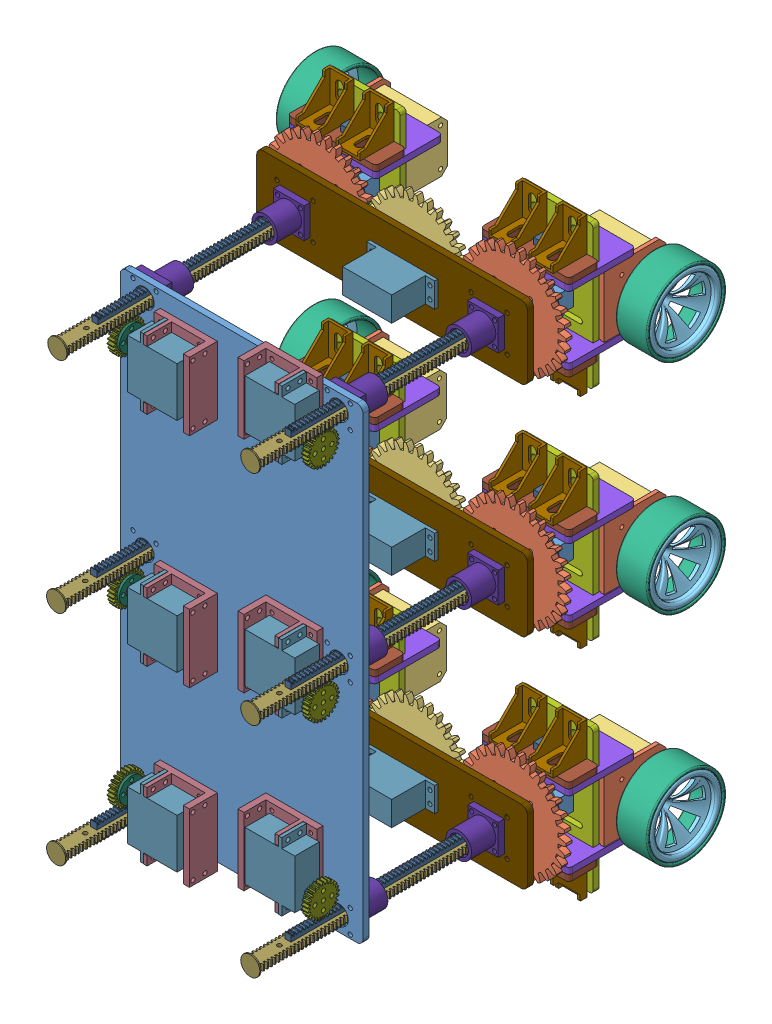
SolidWorks assembly 装配体1A, configuration 默认. Lengths in mm.
Overall size (307.3 487 335.01).
181 component instances, 21 part files, 77 mates.
Components (placement in the parent):
- 6-1: 6 [默认] at (6.6462 9.8364 382.5) size (200 385 5)
- 装配体1-1: 装配体1 [默认] at (-137.0038 190.3841 181.1965) x (0 -1 0) z (1 0 0) size (127 334.01 110.15)
  - 电机支架-1: 电机支架 [默认] at (0.5477 -19.153 31) size (51 51 56)
  - 电机驱动器-1: 电机驱动器 [默认] at (0.5477 7.847 31) size (42.3 42.3 61)
  - 六角联轴器-1: 六角联轴器 [默认] at (0.5477 7.847 16) x (1 0 0) z (0 1 0) size (14 18 12.12)
  - 整个车轮-1: 整个车轮 [默认] at (-1.2111 6.0898 64.1725) x (-0.823184 -0.567775 0) z (0 0 -1) size (84.94 84.94 26)
    - 轮胎-1: 轮胎 [默认] at (-2.4455 0.4479 54.1725) size (63.39 63.18 21.57)
    - 轮胎外-1: 轮胎外 [默认] at (-2.4455 0.4479 48.1725) x (0.923728 0.383049 0) z (0.383049 -0.923728 0) size (65 26 65)
  - 1-1: 1 [默认] at (0.5477 -27.153 60.15) x (1 0 0) z (0 1 0) size (118 63 5)
  - 2-1: 2 [默认] at (31.0477 -24.653 63.65) x (0 0 -1) z (-1 0 0) size (73 55 5)
  - 2-2: 2 [默认] at (-24.9523 -24.653 63.65) x (0 0 -1) z (-1 0 0) size (73 55 5)
  - 2020角件-1: 2020角件 [Default] at (36.0477 -27.153 37.15) x (0 -1 0) z (0 0 1) size (28 28 20)
  - 2020角件-2: 2020角件 [Default] at (-34.9523 -27.153 90.15) x (0 -1 0) z (0 0 -1) size (28 28 20)
  - 3-1: 3 [默认] at (-1.9523 -27.153 66.15) x (1 0 0) z (0 0 -1) size (38 220 5)
  - 3-2: 3 [默认] at (3.0477 -27.153 61.15) x (-1 0 0) z (0 0 1) size (38 220 5)
  - 4-1: 4 [默认] at (-29.9523 -39.653 63.65) x (0 0 -1) z (-1 0 0) size (73 25 5)
  - 2020角件-3: 2020角件 [Default] at (-34.9523 -27.153 57.15) x (0 -1 0) z (0 0 -1) size (28 28 20)
  - 4-2: 4 [默认] at (36.0477 -39.653 63.65) x (0 0 -1) z (-1 0 0) size (73 25 5)
  - 2020角件-4: 2020角件 [Default] at (36.0477 -27.153 70.15) x (0 -1 0) z (0 0 1) size (28 28 20)
  - 5-1: 5 [默认] at (-1.9523 -260.723 -17.3052) x (0 0 -1) z (1 0 0) size (15.81 251 15.81)
- 装配体3-1: 装配体3 [默认] at (-35.9644 156.0912 456.1) x (-1 0 0) z (0 0 -1) size (62.5 56.25 28.25)
  - 20KG大舵机支架-1: 20KG大舵机支架 [Default] at (3.3894 4.911 63.6) size (47 56 25.2)
  - 20KG大舵机-1: 20KG大舵机 [Default] at (26.3894 5.161 53.5) x (0 -1 0) z (-1 0 0) size (56 20.2 45)
  - 舵盘 (1)-1: 舵盘 (1) [默认] at (34.8894 14.911 53.5) x (0 0 1) z (-1 0 0) size (20 20 4.5)
  - 齿轮3-1: 齿轮3 [默认] at (39.8894 -17.7771 74.1398) x (0 0 1) z (-1 0 0) size (26.3 26.25 5)
- 装配体1-2: 装配体1 [默认] at (-137.0038 10.3841 182.1965) x (0 -1 0) z (1 0 0) size (127 334.01 110.15)
  - 电机支架-1: 电机支架 [默认] at (0.5477 -19.153 31) size (51 51 56)
  - 电机驱动器-1: 电机驱动器 [默认] at (0.5477 7.847 31) size (42.3 42.3 61)
  - 六角联轴器-1: 六角联轴器 [默认] at (0.5477 7.847 16) x (1 0 0) z (0 1 0) size (14 18 12.12)
  - 整个车轮-1: 整个车轮 [默认] at (-1.2111 6.0898 64.1725) x (-0.823184 -0.567775 0) z (0 0 -1) size (84.94 84.94 26)
    - 轮胎-1: 轮胎 [默认] at (-2.4455 0.4479 54.1725) size (63.39 63.18 21.57)
    - 轮胎外-1: 轮胎外 [默认] at (-2.4455 0.4479 48.1725) x (0.923728 0.383049 0) z (0.383049 -0.923728 0) size (65 26 65)
  - 1-1: 1 [默认] at (0.5477 -27.153 60.15) x (1 0 0) z (0 1 0) size (118 63 5)
  - 2-1: 2 [默认] at (31.0477 -24.653 63.65) x (0 0 -1) z (-1 0 0) size (73 55 5)
  - 2-2: 2 [默认] at (-24.9523 -24.653 63.65) x (0 0 -1) z (-1 0 0) size (73 55 5)
  - 2020角件-1: 2020角件 [Default] at (36.0477 -27.153 37.15) x (0 -1 0) z (0 0 1) size (28 28 20)
  - 2020角件-2: 2020角件 [Default] at (-34.9523 -27.153 90.15) x (0 -1 0) z (0 0 -1) size (28 28 20)
  - 3-1: 3 [默认] at (-1.9523 -27.153 66.15) x (1 0 0) z (0 0 -1) size (38 220 5)
  - 3-2: 3 [默认] at (3.0477 -27.153 61.15) x (-1 0 0) z (0 0 1) size (38 220 5)
  - 4-1: 4 [默认] at (-29.9523 -39.653 63.65) x (0 0 -1) z (-1 0 0) size (73 25 5)
  - 2020角件-3: 2020角件 [Default] at (-34.9523 -27.153 57.15) x (0 -1 0) z (0 0 -1) size (28 28 20)
  - 4-2: 4 [默认] at (36.0477 -39.653 63.65) x (0 0 -1) z (-1 0 0) size (73 25 5)
  - 2020角件-4: 2020角件 [Default] at (36.0477 -27.153 70.15) x (0 -1 0) z (0 0 1) size (28 28 20)
  - 5-1: 5 [默认] at (-1.9523 -260.723 -17.3052) x (0 0 -1) z (1 0 0) size (15.81 251 15.81)
- 装配体3-2: 装配体3 [默认] at (-35.9644 -23.777 456.1) x (-1 0 0) z (0 0 -1) size (62.5 56.25 28.25)
  - 20KG大舵机支架-1: 20KG大舵机支架 [Default] at (3.3894 4.911 63.6) size (47 56 25.2)
  - 20KG大舵机-1: 20KG大舵机 [Default] at (26.3894 5.161 53.5) x (0 -1 0) z (-1 0 0) size (56 20.2 45)
  - 舵盘 (1)-1: 舵盘 (1) [默认] at (34.8894 14.911 53.5) x (0 0 1) z (-1 0 0) size (20 20 4.5)
  - 齿轮3-1: 齿轮3 [默认] at (39.8894 -17.7771 74.1398) x (0 0 1) z (-1 0 0) size (26.3 26.25 5)
- 装配体1-3: 装配体1 [默认] at (-137.0038 -169.6159 182.1965) x (0 -1 0) z (1 0 0) size (127 334.01 110.15)
  - 电机支架-1: 电机支架 [默认] at (0.5477 -19.153 31) size (51 51 56)
  - 电机驱动器-1: 电机驱动器 [默认] at (0.5477 7.847 31) size (42.3 42.3 61)
  - 六角联轴器-1: 六角联轴器 [默认] at (0.5477 7.847 16) x (1 0 0) z (0 1 0) size (14 18 12.12)
  - 整个车轮-1: 整个车轮 [默认] at (-1.2111 6.0898 64.1725) x (-0.823184 -0.567775 0) z (0 0 -1) size (84.94 84.94 26)
    - 轮胎-1: 轮胎 [默认] at (-2.4455 0.4479 54.1725) size (63.39 63.18 21.57)
    - 轮胎外-1: 轮胎外 [默认] at (-2.4455 0.4479 48.1725) x (0.923728 0.383049 0) z (0.383049 -0.923728 0) size (65 26 65)
  - 1-1: 1 [默认] at (0.5477 -27.153 60.15) x (1 0 0) z (0 1 0) size (118 63 5)
  - 2-1: 2 [默认] at (31.0477 -24.653 63.65) x (0 0 -1) z (-1 0 0) size (73 55 5)
  - 2-2: 2 [默认] at (-24.9523 -24.653 63.65) x (0 0 -1) z (-1 0 0) size (73 55 5)
  - 2020角件-1: 2020角件 [Default] at (36.0477 -27.153 37.15) x (0 -1 0) z (0 0 1) size (28 28 20)
  - 2020角件-2: 2020角件 [Default] at (-34.9523 -27.153 90.15) x (0 -1 0) z (0 0 -1) size (28 28 20)
  - 3-1: 3 [默认] at (-1.9523 -27.153 66.15) x (1 0 0) z (0 0 -1) size (38 220 5)
  - 3-2: 3 [默认] at (3.0477 -27.153 61.15) x (-1 0 0) z (0 0 1) size (38 220 5)
  - 4-1: 4 [默认] at (-29.9523 -39.653 63.65) x (0 0 -1) z (-1 0 0) size (73 25 5)
  - 2020角件-3: 2020角件 [Default] at (-34.9523 -27.153 57.15) x (0 -1 0) z (0 0 -1) size (28 28 20)
  - 4-2: 4 [默认] at (36.0477 -39.653 63.65) x (0 0 -1) z (-1 0 0) size (73 25 5)
  - 2020角件-4: 2020角件 [Default] at (36.0477 -27.153 70.15) x (0 -1 0) z (0 0 1) size (28 28 20)
  - 5-1: 5 [默认] at (-1.9523 -260.723 -17.3052) x (0 0 -1) z (1 0 0) size (15.81 251 15.81)
- 装配体3-3: 装配体3 [默认] at (-35.9644 -166.195 456.1) x (-1 0 0) z (0 0 -1) size (62.5 56.25 28.25)
  - 20KG大舵机支架-1: 20KG大舵机支架 [Default] at (3.3894 4.911 63.6) size (47 56 25.2)
  - 20KG大舵机-1: 20KG大舵机 [Default] at (26.3894 5.161 53.5) x (0 -1 0) z (-1 0 0) size (56 20.2 45)
  - 舵盘 (1)-1: 舵盘 (1) [默认] at (34.8894 14.911 53.5) x (0 0 1) z (-1 0 0) size (20 20 4.5)
  - 齿轮3-1: 齿轮3 [默认] at (39.8894 -17.7771 74.1398) x (0 0 1) z (-1 0 0) size (26.3 26.25 5)
- 装配体1-4: 装配体1 [默认] at (150.2962 -170.7113 182.1965) x (0 1 0) z (-1 0 0) size (127 334.01 110.15)
  - 电机支架-1: 电机支架 [默认] at (0.5477 -19.153 31) size (51 51 56)
  - 电机驱动器-1: 电机驱动器 [默认] at (0.5477 7.847 31) size (42.3 42.3 61)
  - 六角联轴器-1: 六角联轴器 [默认] at (0.5477 7.847 16) x (1 0 0) z (0 1 0) size (14 18 12.12)
  - 整个车轮-1: 整个车轮 [默认] at (-1.2111 6.0898 64.1725) x (-0.823184 -0.567775 0) z (0 0 -1) size (84.94 84.94 26)
    - 轮胎-1: 轮胎 [默认] at (-2.4455 0.4479 54.1725) size (63.39 63.18 21.57)
    - 轮胎外-1: 轮胎外 [默认] at (-2.4455 0.4479 48.1725) x (0.923728 0.383049 0) z (0.383049 -0.923728 0) size (65 26 65)
  - 1-1: 1 [默认] at (0.5477 -27.153 60.15) x (1 0 0) z (0 1 0) size (118 63 5)
  - 2-1: 2 [默认] at (31.0477 -24.653 63.65) x (0 0 -1) z (-1 0 0) size (73 55 5)
  - 2-2: 2 [默认] at (-24.9523 -24.653 63.65) x (0 0 -1) z (-1 0 0) size (73 55 5)
  - 2020角件-1: 2020角件 [Default] at (36.0477 -27.153 37.15) x (0 -1 0) z (0 0 1) size (28 28 20)
  - 2020角件-2: 2020角件 [Default] at (-34.9523 -27.153 90.15) x (0 -1 0) z (0 0 -1) size (28 28 20)
  - 3-1: 3 [默认] at (-1.9523 -27.153 66.15) x (1 0 0) z (0 0 -1) size (38 220 5)
  - 3-2: 3 [默认] at (3.0477 -27.153 61.15) x (-1 0 0) z (0 0 1) size (38 220 5)
  - 4-1: 4 [默认] at (-29.9523 -39.653 63.65) x (0 0 -1) z (-1 0 0) size (73 25 5)
  - 2020角件-3: 2020角件 [Default] at (-34.9523 -27.153 57.15) x (0 -1 0) z (0 0 -1) size (28 28 20)
  - 4-2: 4 [默认] at (36.0477 -39.653 63.65) x (0 0 -1) z (-1 0 0) size (73 25 5)
  - 2020角件-4: 2020角件 [Default] at (36.0477 -27.153 70.15) x (0 -1 0) z (0 0 1) size (28 28 20)
  - 5-1: 5 [默认] at (-1.9523 -260.723 -17.3052) x (0 0 -1) z (1 0 0) size (15.81 251 15.81)
- 装配体3-4: 装配体3 [默认] at (49.2569 -136.3794 456.1) x (1 0 0) z (0 0 -1) size (62.5 56.25 28.25)
  - 20KG大舵机支架-1: 20KG大舵机支架 [Default] at (3.3894 4.911 63.6) size (47 56 25.2)
  - 20KG大舵机-1: 20KG大舵机 [Default] at (26.3894 5.161 53.5) x (0 -1 0) z (-1 0 0) size (56 20.2 45)
  - 舵盘 (1)-1: 舵盘 (1) [默认] at (34.8894 14.911 53.5) x (0 0 1) z (-1 0 0) size (20 20 4.5)
  - 齿轮3-1: 齿轮3 [默认] at (39.8894 -17.7771 74.1398) x (0 0 1) z (-1 0 0) size (26.3 26.25 5)
- 装配体1-5: 装配体1 [默认] at (150.2962 9.2887 182.1965) x (0 1 0) z (-1 0 0) size (127 334.01 110.15)
  - 电机支架-1: 电机支架 [默认] at (0.5477 -19.153 31) size (51 51 56)
  - 电机驱动器-1: 电机驱动器 [默认] at (0.5477 7.847 31) size (42.3 42.3 61)
  - 六角联轴器-1: 六角联轴器 [默认] at (0.5477 7.847 16) x (1 0 0) z (0 1 0) size (14 18 12.12)
  - 整个车轮-1: 整个车轮 [默认] at (-1.2111 6.0898 64.1725) x (-0.823184 -0.567775 0) z (0 0 -1) size (84.94 84.94 26)
    - 轮胎-1: 轮胎 [默认] at (-2.4455 0.4479 54.1725) size (63.39 63.18 21.57)
    - 轮胎外-1: 轮胎外 [默认] at (-2.4455 0.4479 48.1725) x (0.923728 0.383049 0) z (0.383049 -0.923728 0) size (65 26 65)
  - 1-1: 1 [默认] at (0.5477 -27.153 60.15) x (1 0 0) z (0 1 0) size (118 63 5)
  - 2-1: 2 [默认] at (31.0477 -24.653 63.65) x (0 0 -1) z (-1 0 0) size (73 55 5)
  - 2-2: 2 [默认] at (-24.9523 -24.653 63.65) x (0 0 -1) z (-1 0 0) size (73 55 5)
  - 2020角件-1: 2020角件 [Default] at (36.0477 -27.153 37.15) x (0 -1 0) z (0 0 1) size (28 28 20)
  - 2020角件-2: 2020角件 [Default] at (-34.9523 -27.153 90.15) x (0 -1 0) z (0 0 -1) size (28 28 20)
  - 3-1: 3 [默认] at (-1.9523 -27.153 66.15) x (1 0 0) z (0 0 -1) size (38 220 5)
  - 3-2: 3 [默认] at (3.0477 -27.153 61.15) x (-1 0 0) z (0 0 1) size (38 220 5)
  - 4-1: 4 [默认] at (-29.9523 -39.653 63.65) x (0 0 -1) z (-1 0 0) size (73 25 5)
  - 2020角件-3: 2020角件 [Default] at (-34.9523 -27.153 57.15) x (0 -1 0) z (0 0 -1) size (28 28 20)
  - 4-2: 4 [默认] at (36.0477 -39.653 63.65) x (0 0 -1) z (-1 0 0) size (73 25 5)
  - 2020角件-4: 2020角件 [Default] at (36.0477 -27.153 70.15) x (0 -1 0) z (0 0 1) size (28 28 20)
  - 5-1: 5 [默认] at (-1.9523 -260.723 -17.3052) x (0 0 -1) z (1 0 0) size (15.81 251 15.81)
- 装配体3-5: 装配体3 [默认] at (49.2569 4.8974 456.1) x (1 0 0) z (0 0 -1) size (62.5 56.25 28.25)
  - 20KG大舵机支架-1: 20KG大舵机支架 [Default] at (3.3894 4.911 63.6) size (47 56 25.2)
  - 20KG大舵机-1: 20KG大舵机 [Default] at (26.3894 5.161 53.5) x (0 -1 0) z (-1 0 0) size (56 20.2 45)
  - 舵盘 (1)-1: 舵盘 (1) [默认] at (34.8894 14.911 53.5) x (0 0 1) z (-1 0 0) size (20 20 4.5)
  - 齿轮3-1: 齿轮3 [默认] at (39.8894 -17.7771 74.1398) x (0 0 1) z (-1 0 0) size (26.3 26.25 5)
- 装配体1-6: 装配体1 [默认] at (150.2962 189.2887 182.1965) x (0 1 0) z (-1 0 0) size (127 334.01 110.15)
  - 电机支架-1: 电机支架 [默认] at (0.5477 -19.153 31) size (51 51 56)
  - 电机驱动器-1: 电机驱动器 [默认] at (0.5477 7.847 31) size (42.3 42.3 61)
  - 六角联轴器-1: 六角联轴器 [默认] at (0.5477 7.847 16) x (1 0 0) z (0 1 0) size (14 18 12.12)
  - 整个车轮-1: 整个车轮 [默认] at (-1.2111 6.0898 64.1725) x (-0.823184 -0.567775 0) z (0 0 -1) size (84.94 84.94 26)
    - 轮胎-1: 轮胎 [默认] at (-2.4455 0.4479 54.1725) size (63.39 63.18 21.57)
    - 轮胎外-1: 轮胎外 [默认] at (-2.4455 0.4479 48.1725) x (0.923728 0.383049 0) z (0.383049 -0.923728 0) size (65 26 65)
  - 1-1: 1 [默认] at (0.5477 -27.153 60.15) x (1 0 0) z (0 1 0) size (118 63 5)
  - 2-1: 2 [默认] at (31.0477 -24.653 63.65) x (0 0 -1) z (-1 0 0) size (73 55 5)
  - 2-2: 2 [默认] at (-24.9523 -24.653 63.65) x (0 0 -1) z (-1 0 0) size (73 55 5)
  - 2020角件-1: 2020角件 [Default] at (36.0477 -27.153 37.15) x (0 -1 0) z (0 0 1) size (28 28 20)
  - 2020角件-2: 2020角件 [Default] at (-34.9523 -27.153 90.15) x (0 -1 0) z (0 0 -1) size (28 28 20)
  - 3-1: 3 [默认] at (-1.9523 -27.153 66.15) x (1 0 0) z (0 0 -1) size (38 220 5)
  - 3-2: 3 [默认] at (3.0477 -27.153 61.15) x (-1 0 0) z (0 0 1) size (38 220 5)
  - 4-1: 4 [默认] at (-29.9523 -39.653 63.65) x (0 0 -1) z (-1 0 0) size (73 25 5)
  - 2020角件-3: 2020角件 [Default] at (-34.9523 -27.153 57.15) x (0 -1 0) z (0 0 -1) size (28 28 20)
  - 4-2: 4 [默认] at (36.0477 -39.653 63.65) x (0 0 -1) z (-1 0 0) size (73 25 5)
  - 2020角件-4: 2020角件 [Default] at (36.0477 -27.153 70.15) x (0 -1 0) z (0 0 1) size (28 28 20)
  - 5-1: 5 [默认] at (-1.9523 -260.723 -17.3052) x (0 0 -1) z (1 0 0) size (15.81 251 15.81)
- 装配体3-6: 装配体3 [默认] at (49.2569 185.8791 456.1) x (1 0 0) z (0 0 -1) size (62.5 56.25 28.25)
  - 20KG大舵机支架-1: 20KG大舵机支架 [Default] at (3.3894 4.911 63.6) size (47 56 25.2)
  - 20KG大舵机-1: 20KG大舵机 [Default] at (26.3894 5.161 53.5) x (0 -1 0) z (-1 0 0) size (56 20.2 45)
  - 舵盘 (1)-1: 舵盘 (1) [默认] at (34.8894 14.911 53.5) x (0 0 1) z (-1 0 0) size (20 20 4.5)
  - 齿轮3-1: 齿轮3 [默认] at (39.8894 -17.7771 74.1398) x (0 0 1) z (-1 0 0) size (26.3 26.25 5)
- 8-1: 8 [默认] at (86.6462 -170.1636 382.5) x (-1 0 0) z (0 0 -1) size (25 25 25)
- 8-2: 8 [默认] at (86.6462 9.8364 382.5) x (-1 0 0) z (0 0 -1) size (25 25 25)
- 8-3: 8 [默认] at (86.6462 189.8364 382.5) x (-1 0 0) z (0 0 -1) size (25 25 25)
- 8-4: 8 [默认] at (-73.3538 189.8364 382.5) x (-1 0 0) z (0 0 -1) size (25 25 25)
- 8-5: 8 [默认] at (-73.3538 9.8364 382.5) x (-1 0 0) z (0 0 -1) size (25 25 25)
- 8-6: 8 [默认] at (-73.3538 -170.1636 382.5) x (-1 0 0) z (0 0 -1) size (25 25 25)
- 10-1: 10 [默认] at (6.6462 189.8364 258.5495) size (223 60 5)
- 9-1: 9 [默认] at (86.6462 189.8364 209.3495) size (50 50 30)
- 齿轮4-1: 齿轮4 [默认] at (86.6462 189.8364 239.3495) size (88 87.71 5)
- 齿轮4-2: 齿轮4 [默认] at (-73.3538 189.8364 244.3495) x (-1 0 0) z (0 0 -1) size (88 87.71 5)
- 9-2: 9 [默认] at (-73.3538 189.8364 209.3495) size (50 50 30)
- 20KG大舵机-1: 20KG大舵机 [Default] at (16.4351 190.0741 252.8495) size (56 20.2 45)
- 舵盘 (1)-1: 舵盘 (1) [默认] at (6.6851 190.0741 244.3495) size (20 20 4.5)
- 齿轮5-3: 齿轮5 [默认] at (6.6851 190.0741 239.4745) x (-0.001815 -0.999998 0) z (0 0 1) size (83.6 83.33 4.75)
- 8-7: 8 [默认] at (-73.3538 189.8364 263.5495) size (25 25 25)
- 8-8: 8 [默认] at (86.6462 189.8364 263.5495) size (25 25 25)
- 9-3: 9 [默认] at (86.6462 9.8364 209.3495) size (50 50 30)
- 9-4: 9 [默认] at (86.6462 -170.1636 209.3495) size (50 50 30)
- 9-5: 9 [默认] at (-73.3538 9.8364 209.3495) size (50 50 30)
- 9-6: 9 [默认] at (-73.3538 -170.1636 209.3495) size (50 50 30)
- 齿轮4-3: 齿轮4 [默认] at (-73.3538 9.8364 244.3495) x (-1 0 0) z (0 0 -1) size (88 87.71 5)
- 齿轮4-4: 齿轮4 [默认] at (-73.3538 -170.1636 244.3495) x (-1 0 0) z (0 0 -1) size (88 87.71 5)
- 舵盘 (1)-2: 舵盘 (1) [默认] at (6.6851 10.0741 244.3495) size (20 20 4.5)
- 舵盘 (1)-3: 舵盘 (1) [默认] at (6.6851 -169.9259 244.3495) size (20 20 4.5)
- 齿轮5-4: 齿轮5 [默认] at (6.6851 10.0741 239.4745) x (-0.001815 -0.999998 0) z (0 0 1) size (83.6 83.33 4.75)
- 齿轮5-5: 齿轮5 [默认] at (6.6851 -169.9259 239.4745) x (-0.001815 -0.999998 0) z (0 0 1) size (83.6 83.33 4.75)
- 齿轮4-5: 齿轮4 [默认] at (86.6462 9.8364 239.3495) size (88 87.71 5)
- 齿轮4-6: 齿轮4 [默认] at (86.6462 -170.1636 239.3495) size (88 87.71 5)
- 8-9: 8 [默认] at (-73.3538 9.8364 263.5495) size (25 25 25)
- 8-10: 8 [默认] at (-73.3538 -170.1636 263.5495) size (25 25 25)
- 8-11: 8 [默认] at (86.6462 9.8364 263.5495) size (25 25 25)
- 8-12: 8 [默认] at (86.6462 -170.1636 263.5495) size (25 25 25)
- 20KG大舵机-2: 20KG大舵机 [Default] at (16.4351 10.0741 252.8495) size (56 20.2 45)
- 20KG大舵机-3: 20KG大舵机 [Default] at (16.4351 -169.9259 252.8495) size (56 20.2 45)
- 10-2: 10 [默认] at (6.6462 9.8364 258.5495) size (223 60 5)
- 10-3: 10 [默认] at (6.6462 -170.1636 258.5495) size (223 60 5)
Mates (geometry in assembly coordinates):
- 重合1: coincident anti-aligned: plane of 6-1 through (6.6462 9.8364 387.5) normal (0 0 1); plane of 装配体3-1/20KG大舵机支架-1 through (-39.3538 161.0022 387.5) normal (0 0 -1)
- 平行1: parallel aligned: plane of 6-1 through (6.6462 9.8364 387.5) normal (0 0 1); plane of 装配体1-1/1-1 through (-101.8538 133.8364 208.3495) normal (0 0 1)
- 平行2: parallel aligned: plane of 6-1 through (-93.3538 -182.6636 387.5) normal (-1 0 0); plane of 装配体1-1/电机支架-1 through (-109.0038 189.8364 200.3495) normal (-1 0 0)
- 同心1: concentric aligned: circle of 6-1; circle of 装配体1-1/5-1
- 重合4: coincident aligned: plane of 装配体1-1/3-2 through (-75.8538 187.3364 208.3495) normal (-1 0 0); plane of 装配体3-1/齿轮3-1 through (-75.8538 174.0294 407.661) normal (-1 0 0)
- 距离1: distance = 13.3343 mm aligned: plane of 装配体3-1/20KG大舵机支架-1 through (-18.3538 189.0022 387.5) normal (0 1 0); plane of 6-1 through (106.6462 202.3364 387.5) normal (0 1 0)
- 平行3: parallel aligned: plane of 6-1 through (6.6462 9.8364 387.5) normal (0 0 1); plane of 装配体1-2/1-1 through (-101.8538 -46.1636 209.3495) normal (0 0 1)
- 同心6: concentric aligned: cylinder of 6-1 through (-73.3538 9.8364 387.5) axis (0 0 -1) radius 7.9057; cylinder of 装配体1-2/5-1 through (-73.3538 9.8364 460.3495) axis (0 0 -1) radius 7.905
- 平行4: parallel aligned: plane of 6-1 through (-93.3538 -182.6636 387.5) normal (-1 0 0); plane of 装配体1-2/电机支架-1 through (-109.0038 9.8364 201.3495) normal (-1 0 0)
- 重合8: coincident anti-aligned: plane of 6-1 through (6.6462 9.8364 387.5) normal (0 0 1); plane of 装配体3-2/20KG大舵机支架-1 through (-39.3538 -18.866 387.5) normal (0 0 -1)
- 重合9: coincident aligned: plane of 装配体1-2/3-2 through (-75.8538 7.3364 209.3495) normal (-1 0 0); plane of 装配体3-2/齿轮3-1 through (-75.8538 -5.8388 407.661) normal (-1 0 0)
- 距离2: distance = 143.7976 mm aligned: plane of 装配体3-2/20KG大舵机-1 through (-21.3538 -38.866 412.7) normal (0 -1 0); plane of 6-1 through (106.6462 -182.6636 387.5) normal (0 -1 0)
- 同心7: concentric aligned: cylinder of 6-1 through (-73.3538 -170.1636 387.5) axis (0 0 -1) radius 7.9057; cylinder of 装配体1-3/5-1 through (-73.3538 -170.1636 460.3495) axis (0 0 -1) radius 7.905
- 平行6: parallel aligned: plane of 6-1 through (-93.3538 -182.6636 387.5) normal (-1 0 0); plane of 装配体1-3/电机支架-1 through (-109.0038 -170.1636 201.3495) normal (-1 0 0)
- 重合13: coincident anti-aligned: plane of 6-1 through (6.6462 9.8364 387.5) normal (0 0 1); plane of 装配体3-3/20KG大舵机支架-1 through (-39.3538 -161.284 387.5) normal (0 0 -1)
- 重合14: coincident aligned: plane of 装配体1-3/3-1 through (-75.8538 -167.6636 209.3495) normal (-1 0 0); plane of 装配体3-3/齿轮3-1 through (-75.8538 -148.2568 407.661) normal (-1 0 0)
- 距离3: distance = 49.3796 mm anti-aligned: plane of 装配体3-3/20KG大舵机支架-1 through (-18.3538 -133.284 387.5) normal (0 1 0); plane of 6-1 through (106.6462 -182.6636 387.5) normal (0 -1 0)
- 同心8: concentric aligned: cylinder of 6-1 through (86.6462 -170.1636 387.5) axis (0 0 -1) radius 7.9057; cylinder of 装配体1-4/5-1 through (86.6462 -170.1636 460.3495) axis (0 0 -1) radius 7.905
- 平行7: parallel aligned: plane of 6-1 through (106.6462 -182.6636 387.5) normal (1 0 0); plane of 装配体1-4/电机支架-1 through (122.2962 -170.1636 201.3495) normal (1 0 0)
- 重合16: coincident anti-aligned: plane of 6-1 through (6.6462 9.8364 387.5) normal (0 0 1); plane of 装配体3-4/20KG大舵机支架-1 through (52.6462 -141.2903 387.5) normal (0 0 -1)
- 重合17: coincident aligned: plane of 装配体1-4/3-2 through (89.1462 -167.6636 209.3495) normal (1 0 0); plane of 装配体3-4/齿轮3-1 through (89.1462 -154.3175 407.661) normal (1 0 0)
- 距离4: distance = 13.3732 mm aligned: plane of 装配体3-4/20KG大舵机支架-1 through (31.6462 -169.2903 387.5) normal (0 -1 0); plane of 6-1 through (106.6462 -182.6636 387.5) normal (0 -1 0)
- 同心9: concentric anti-aligned: cylinder of 6-1 through (86.6462 9.8364 387.5) axis (0 0 -1) radius 7.9057; circle of 装配体1-5/5-1
- 平行8: parallel anti-aligned: plane of 6-1 through (106.6462 -182.6636 387.5) normal (1 0 0); plane of 装配体1-5/电机驱动器-1 through (72.2962 9.8364 174.3495) normal (-1 0 0)
- 重合21: coincident anti-aligned: plane of 6-1 through (6.6462 9.8364 387.5) normal (0 0 1); plane of 装配体3-5/20KG大舵机支架-1 through (52.6462 -0.0136 387.5) normal (0 0 -1)
- 重合23: coincident aligned: plane of 装配体1-5/3-1 through (89.1462 7.3364 209.3495) normal (1 0 0); plane of 装配体3-5/齿轮3-1 through (89.1462 -13.0408 407.661) normal (1 0 0)
- 同心10: concentric anti-aligned: cylinder of 6-1 through (86.6462 189.8364 387.5) axis (0 0 -1) radius 7.9057; circle of 装配体1-6/5-1
- 平行9: parallel aligned: plane of 6-1 through (106.6462 -182.6636 387.5) normal (1 0 0); plane of 装配体1-6/电机支架-1 through (122.2962 189.8364 201.3495) normal (1 0 0)
- 重合25: coincident anti-aligned: plane of 6-1 through (6.6462 9.8364 387.5) normal (0 0 1); plane of 装配体3-6/20KG大舵机支架-1 through (52.6462 180.9681 387.5) normal (0 0 -1)
- 重合26: coincident aligned: plane of 装配体1-6/3-1 through (89.1462 187.3364 209.3495) normal (1 0 0); plane of 装配体3-6/齿轮3-1 through (89.1462 167.9409 407.661) normal (1 0 0)
- 距离5: distance = 6.6317 mm aligned: plane of 6-1 through (106.6462 202.3364 387.5) normal (0 1 0); plane of 装配体3-6/20KG大舵机支架-1 through (31.6462 208.9681 387.5) normal (0 1 0)
- 重合28: coincident anti-aligned: plane of 6-1 through (6.6462 9.8364 382.5) normal (0 0 -1); plane of 8-1 through (86.6462 -170.1636 382.5) normal (0 0 1)
- 同心11: concentric aligned: cylinder of 装配体1-4/5-1 through (86.6462 -170.1636 460.3495) axis (0 0 -1) radius 7.905; cylinder of 8-1 through (86.6462 -170.1636 382.5) axis (0 0 -1) radius 7.905
- 重合29: coincident aligned: plane of 6-1 through (106.6462 -182.6636 387.5) normal (0 -1 0); plane of 8-1 through (74.1462 -182.6636 377.5) normal (0 -1 0)
- 重合30: coincident anti-aligned: plane of 6-1 through (6.6462 9.8364 382.5) normal (0 0 -1); plane of 8-4 through (-73.3538 189.8364 382.5) normal (0 0 1)
- 同心12: concentric aligned: cylinder of 装配体1-1/5-1 through (-73.3538 189.8364 459.3495) axis (0 0 -1) radius 7.905; cylinder of 8-4 through (-73.3538 189.8364 382.5) axis (0 0 -1) radius 7.905
- 重合31: coincident aligned: plane of 6-1 through (106.6462 202.3364 387.5) normal (0 1 0); plane of 8-4 through (-85.8538 202.3364 377.5) normal (0 1 0)
- 重合32: coincident anti-aligned: plane of 6-1 through (6.6462 9.8364 382.5) normal (0 0 -1); plane of 8-5 through (-73.3538 9.8364 382.5) normal (0 0 1)
- 同心13: concentric aligned: cylinder of 装配体1-2/5-1 through (-73.3538 9.8364 460.3495) axis (0 0 -1) radius 7.905; cylinder of 8-5 through (-73.3538 9.8364 382.5) axis (0 0 -1) radius 7.905
- 平行10: parallel aligned: plane of 6-1 through (-93.3538 -182.6636 387.5) normal (-1 0 0); plane of 8-5 through (-85.8538 -2.6636 377.5) normal (-1 0 0)
- 重合34: coincident anti-aligned: plane of 6-1 through (6.6462 9.8364 382.5) normal (0 0 -1); plane of 8-6 through (-73.3538 -170.1636 382.5) normal (0 0 1)
- 同心14: concentric aligned: cylinder of 装配体1-3/5-1 through (-73.3538 -170.1636 460.3495) axis (0 0 -1) radius 7.905; cylinder of 8-6 through (-73.3538 -170.1636 382.5) axis (0 0 -1) radius 7.905
- 平行11: parallel aligned: plane of 6-1 through (-93.3538 -182.6636 387.5) normal (-1 0 0); plane of 8-6 through (-85.8538 -182.6636 377.5) normal (-1 0 0)
- 重合36: coincident anti-aligned: plane of 6-1 through (6.6462 9.8364 382.5) normal (0 0 -1); plane of 8-2 through (86.6462 9.8364 382.5) normal (0 0 1)
- 同心15: concentric aligned: cylinder of 装配体1-5/5-1 through (86.6462 9.8364 460.3495) axis (0 0 -1) radius 7.905; cylinder of 8-2 through (86.6462 9.8364 382.5) axis (0 0 -1) radius 7.905
- 平行12: parallel aligned: plane of 6-1 through (106.6462 -182.6636 387.5) normal (1 0 0); plane of 8-2 through (99.1462 -2.6636 377.5) normal (1 0 0)
- 重合38: coincident anti-aligned: plane of 6-1 through (6.6462 9.8364 382.5) normal (0 0 -1); plane of 8-3 through (86.6462 189.8364 382.5) normal (0 0 1)
- 同心16: concentric aligned: cylinder of 装配体1-6/5-1 through (86.6462 189.8364 460.3495) axis (0 0 -1) radius 7.905; cylinder of 8-3 through (86.6462 189.8364 382.5) axis (0 0 -1) radius 7.905
- 重合39: coincident aligned: plane of 6-1 through (106.6462 202.3364 387.5) normal (0 1 0); plane of 8-3 through (74.1462 202.3364 377.5) normal (0 1 0)
- 重合40: coincident: plane of 装配体1-1/5-1 through (-73.3538 189.8364 459.3495) normal (0 0 1); moEndPointRef_w of 装配体1-6/5-1
- 重合41: coincident aligned: plane of 装配体1-2/5-1 through (-73.3538 9.8364 460.3495) normal (0 0 1); plane of 装配体1-5/5-1 through (86.6462 9.8364 460.3495) normal (0 0 1)
- 重合42: coincident aligned: plane of 装配体1-3/5-1 through (-73.3538 -170.1636 460.3495) normal (0 0 1); plane of 装配体1-4/5-1 through (86.6462 -170.1636 460.3495) normal (0 0 1)
- 同心17: concentric aligned: cylinder of 装配体1-6/5-1 through (86.6462 189.8364 460.3495) axis (0 0 -1) radius 7.905; cylinder of 10-1 through (86.6462 189.8364 263.5495) axis (0 0 -1) radius 7.905
- 同心19: concentric anti-aligned: circle of 装配体1-1/5-1; cylinder of 10-1 through (-73.3538 189.8364 263.5495) axis (0 0 -1) radius 7.905
- 重合43: coincident anti-aligned: plane of 装配体1-6/3-1 through (84.1462 187.3364 209.3495) normal (-1 0 0); plane of 9-1 through (84.1462 177.3364 229.3495) normal (1 0 0)
- 重合44: coincident anti-aligned: plane of 装配体1-6/5-1 through (167.6014 187.3364 442.9194) normal (0 -1 0); plane of 9-1 through (97.1462 187.3364 229.3495) normal (0 1 0)
- 重合45: coincident anti-aligned: plane of 装配体1-6/1-1 through (115.1462 245.8364 209.3495) normal (0 0 1); plane of 9-1 through (86.6462 189.8364 209.3495) normal (0 0 -1)
- 同心20: concentric anti-aligned: cylinder of 9-1 through (101.4955 204.6857 239.3495) axis (0 0 -1) radius 1.75; cylinder of 齿轮4-1 through (101.4955 204.6857 234.3495) axis (0 0 1) radius 1.75
- 同心21: concentric anti-aligned: cylinder of 9-1 through (71.797 204.6857 239.3495) axis (0 0 -1) radius 1.75; cylinder of 齿轮4-1 through (71.797 204.6857 234.3495) axis (0 0 1) radius 1.75
- 重合46: coincident anti-aligned: plane of 9-1 through (86.6462 189.8364 239.3495) normal (0 0 1); plane of 齿轮4-1 through (67.957 196.8673 239.3495) normal (0 0 -1)
- 平行13: parallel aligned: plane of 10-1 through (113.1462 219.8364 263.5495) normal (0 1 0); plane of 20KG大舵机-1 through (-3.8149 200.1741 293.8495) normal (0 1 0)
- 重合47: coincident anti-aligned: plane of 10-1 through (113.1462 214.8364 263.5495) normal (0 0 1); plane of 20KG大舵机-1 through (16.4351 190.0741 263.5495) normal (0 0 -1)
- 同心23: concentric aligned: cylinder of 20KG大舵机-1 through (6.6851 190.0741 248.8495) axis (0 0 1) radius 2; cylinder of 舵盘 (1)-1 through (6.6851 190.0741 240.3495) axis (0 0 1) radius 1.65
- 重合48: coincident anti-aligned: plane of 20KG大舵机-1 through (6.6851 190.0741 248.8495) normal (0 0 -1); plane of 舵盘 (1)-1 through (6.6851 190.0741 248.8495) normal (0 0 1)
- 同心28: concentric anti-aligned: cylinder of 20KG大舵机-1 through (6.6851 190.0741 248.8495) axis (0 0 1) radius 2; cylinder of 齿轮5-3 through (6.6851 190.0741 244.3495) axis (0 0 -1) radius 1.6625
- 同心30: concentric aligned: cylinder of 10-1 through (40.4351 195.0741 263.5495) axis (0 0 -1) radius 1.75; cylinder of 20KG大舵机-1 through (40.4351 195.0741 266.1495) axis (0 0 -1) radius 1.75
- 同心31: concentric aligned: cylinder of 10-1 through (40.4351 185.0741 263.5495) axis (0 0 -1) radius 1.75; cylinder of 20KG大舵机-1 through (40.4351 185.0741 266.1495) axis (0 0 -1) radius 1.75
- 重合51: coincident aligned: plane of 齿轮4-1 through (67.957 196.8673 244.3495) normal (0 0 1); plane of 齿轮5-3 through (13.3967 207.8168 244.3495) normal (0 0 1)
- 重合52: coincident anti-aligned: plane of 舵盘 (1)-1 through (6.6851 190.0741 244.3495) normal (0 0 -1); plane of 齿轮5-3 through (13.3967 207.8168 244.3495) normal (0 0 1)
- 同心32: concentric anti-aligned: cylinder of 10-1 through (-73.3538 189.8364 263.5495) axis (0 0 -1) radius 7.905; cylinder of 8-7 through (-73.3538 189.8364 263.5495) axis (0 0 1) radius 7.905
- 重合53: coincident anti-aligned: plane of 10-1 through (113.1462 214.8364 263.5495) normal (0 0 1); plane of 8-7 through (-73.3538 189.8364 263.5495) normal (0 0 -1)
- 平行14: parallel aligned: plane of 10-1 through (113.1462 219.8364 263.5495) normal (0 1 0); plane of 8-7 through (-60.8538 202.3364 268.5495) normal (0 1 0)
- 同心33: concentric aligned: cylinder of 10-1 through (86.6462 189.8364 263.5495) axis (0 0 -1) radius 7.905; cylinder of 8-8 through (86.6462 189.8364 288.5495) axis (0 0 -1) radius 10.5
- 平行15: parallel aligned: plane of 10-1 through (113.1462 219.8364 263.5495) normal (0 1 0); plane of 8-8 through (99.1462 202.3364 268.5495) normal (0 1 0)
- 重合54: coincident anti-aligned: plane of 10-1 through (113.1462 214.8364 263.5495) normal (0 0 1); plane of 8-8 through (86.6462 189.8364 263.5495) normal (0 0 -1)
- 重合56: coincident anti-aligned: plane of 装配体1-4/1-1 through (115.1462 -114.1636 209.3495) normal (0 0 1); plane of 9-4 through (86.6462 -170.1636 209.3495) normal (0 0 -1)
- 重合57: coincident anti-aligned: plane of 装配体1-5/1-1 through (115.1462 65.8364 209.3495) normal (0 0 1); plane of 9-3 through (86.6462 9.8364 209.3495) normal (0 0 -1)
